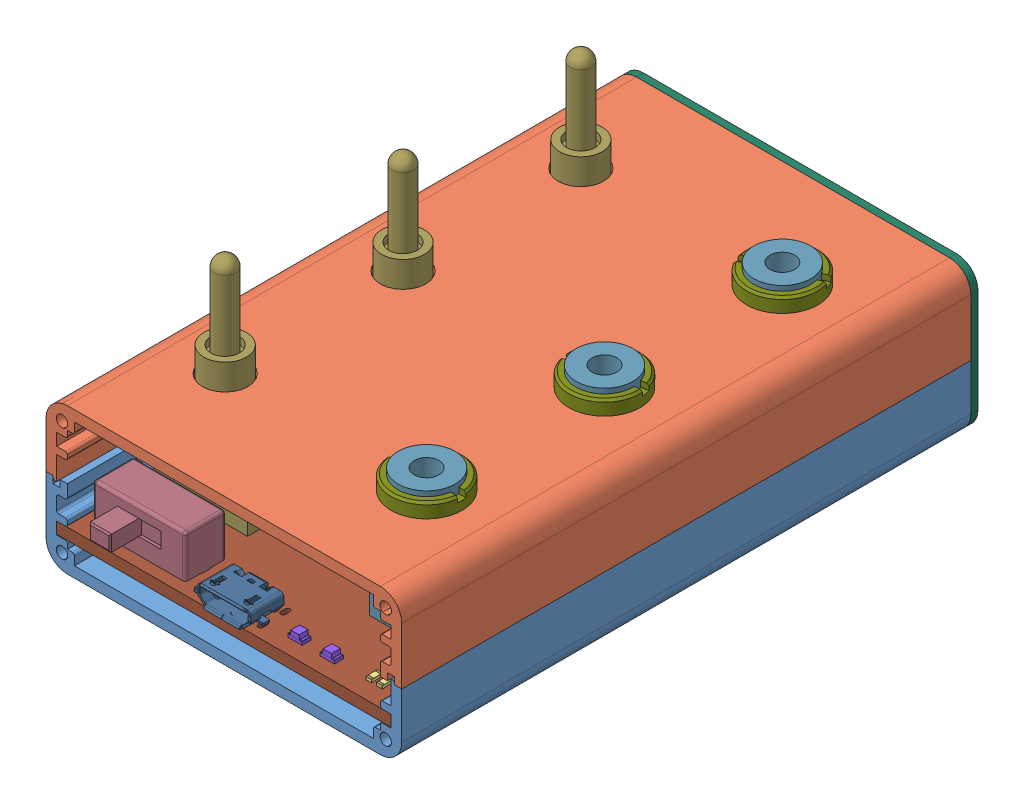
SolidWorks assembly case-full, configuration Default. Lengths in mm.
Overall size (50 35 83.41).
115 component instances, 27 part files, 20 mates.
Components (placement in the parent):
- case-1: case [Default] at (-9.9049 -10.2865 -40) size (50 11 80)
- top-case-2: top-case [Default] at (1.6835 8.41 -40) x (-1 0 0) z (0 0 1) size (50 11 80)
- PCB-assembly-1: PCB-assembly [Default] at (-5.9703 -42.4723 -73.1659) x (0 0 -1) z (0 1 0) size (82.41 47 33.7)
  - ledTruck_PCB.step-1: ledTruck_PCB.step [Default] at (-218.1999 94.1524 35.3841) size (80.38 47 12.68)
    - ledTruck.step-1: ledTruck.step [Default] at origin size (80.38 47 12.68)
      - R_0603_1608Metric.step-1: R_0603_1608Metric.step [Default] at (162.2298 -104.8258 1.65) size (1.6 0.8 0.45)
        - SOLID.step-1: SOLID.step [Default] at origin size (1.6 0.8 0.45)
      - SOT-23-5.step-1: SOT-23-5.step [Default] at (130.302 -76.708 1.65) x (0 -1 0) z (0 0 1) size (2.8 2.9 1.55)
        - SOLID-0.step-1: SOLID-0.step [Default] at origin size (2.8 2.9 1.55)
      - SOT-23-5.step-2: SOT-23-5.step [Default] at (137.16 -76.708 1.65) x (0 -1 0) z (0 0 1) size (2.8 2.9 1.55)
        - SOLID-0.step-1: SOLID-0.step [Default] at origin size (2.8 2.9 1.55)
      - R_0603_1608Metric.step-2: R_0603_1608Metric.step [Default] at (162.433 -79.248 1.65) size (1.6 0.8 0.45)
        - SOLID.step-1: SOLID.step [Default] at origin size (1.6 0.8 0.45)
      - R_0603_1608Metric.step-3: R_0603_1608Metric.step [Default] at (162.433 -76.835 1.65) x (-1 0 0) z (0 0 1) size (1.6 0.8 0.45)
        - SOLID.step-1: SOLID.step [Default] at origin size (1.6 0.8 0.45)
      - R_0603_1608Metric.step-4: R_0603_1608Metric.step [Default] at (108.1929 -114.012 1.65) size (1.6 0.8 0.45)
        - SOLID.step-1: SOLID.step [Default] at origin size (1.6 0.8 0.45)
      - R_0603_1608Metric.step-5: R_0603_1608Metric.step [Default] at (108.1929 -115.512 1.65) size (1.6 0.8 0.45)
        - SOLID.step-1: SOLID.step [Default] at origin size (1.6 0.8 0.45)
      - R_0603_1608Metric.step-6: R_0603_1608Metric.step [Default] at (152.146 -80.01 1.65) size (1.6 0.8 0.45)
        - SOLID.step-1: SOLID.step [Default] at origin size (1.6 0.8 0.45)
      - R_0603_1608Metric.step-7: R_0603_1608Metric.step [Default] at (165.1 -84.836 1.65) x (0 1 0) z (0 0 1) size (1.6 0.8 0.45)
        - SOLID.step-1: SOLID.step [Default] at origin size (1.6 0.8 0.45)
      - R_0603_1608Metric.step-8: R_0603_1608Metric.step [Default] at (137.16 -80.264 1.65) x (-1 0 0) z (0 0 1) size (1.6 0.8 0.45)
        - SOLID.step-1: SOLID.step [Default] at origin size (1.6 0.8 0.45)
      - R_0603_1608Metric.step-9: R_0603_1608Metric.step [Default] at (156.972 -111.506 1.65) x (-1 0 0) z (0 0 1) size (1.6 0.8 0.45)
        - SOLID.step-1: SOLID.step [Default] at origin size (1.6 0.8 0.45)
      - R_0603_1608Metric.step-10: R_0603_1608Metric.step [Default] at (156.972 -107.442 1.65) size (1.6 0.8 0.45)
        - SOLID.step-1: SOLID.step [Default] at origin size (1.6 0.8 0.45)
      - R_0603_1608Metric.step-11: R_0603_1608Metric.step [Default] at (132.842 -113.284 1.65) size (1.6 0.8 0.45)
        - SOLID.step-1: SOLID.step [Default] at origin size (1.6 0.8 0.45)
      - R_0603_1608Metric.step-12: R_0603_1608Metric.step [Default] at (156.972 -109.474 1.65) x (-1 0 0) z (0 0 1) size (1.6 0.8 0.45)
        - SOLID.step-1: SOLID.step [Default] at origin size (1.6 0.8 0.45)
      - R_0603_1608Metric.step-13: R_0603_1608Metric.step [Default] at (156.972 -105.283 1.65) x (-1 0 0) z (0 0 1) size (1.6 0.8 0.45)
        - SOLID.step-1: SOLID.step [Default] at origin size (1.6 0.8 0.45)
      - R_0603_1608Metric.step-14: R_0603_1608Metric.step [Default] at (132.828 -111.379 1.65) size (1.6 0.8 0.45)
        - SOLID.step-1: SOLID.step [Default] at origin size (1.6 0.8 0.45)
      - L_0805_2012Metric.step-1: L_0805_2012Metric.step [Default] at (130.336 -80.264 1.65) x (-1 0 0) z (0 0 1) size (2 1.25 1.25)
        - SOLID-1.step-1: SOLID-1.step [Default] at origin size (2 1.25 1.25)
      - C_0805_2012Metric.step-1: C_0805_2012Metric.step [Default] at (130.302 -87.122 1.65) size (2 1.25 1.25)
        - SOLID-2.step-1: SOLID-2.step [Default] at origin size (2 1.25 1.25)
      - C_0603_1608Metric.step-1: C_0603_1608Metric.step [Default] at (152.146 -78.486 1.65) x (-1 0 0) z (0 0 1) size (1.6 0.8 0.8)
        - SOLID-3.step-1: SOLID-3.step [Default] at origin size (1.6 0.8 0.8)
      - C_0805_2012Metric.step-2: C_0805_2012Metric.step [Default] at (137.16 -83.566 1.65) size (2 1.25 1.25)
        - SOLID-2.step-1: SOLID-2.step [Default] at origin size (2 1.25 1.25)
      - C_0603_1608Metric.step-2: C_0603_1608Metric.step [Default] at (152.146 -76.962 1.65) x (-1 0 0) z (0 0 1) size (1.6 0.8 0.8)
        - SOLID-3.step-1: SOLID-3.step [Default] at origin size (1.6 0.8 0.8)
      - C_0603_1608Metric.step-3: C_0603_1608Metric.step [Default] at (152.146 -75.464 1.65) x (-1 0 0) z (0 0 1) size (1.6 0.8 0.8)
        - SOLID-3.step-1: SOLID-3.step [Default] at origin size (1.6 0.8 0.8)
      - C_0805_2012Metric.step-3: C_0805_2012Metric.step [Default] at (130.302 -83.566 1.65) size (2 1.25 1.25)
        - SOLID-2.step-1: SOLID-2.step [Default] at origin size (2 1.25 1.25)
      - C_0603_1608Metric.step-4: C_0603_1608Metric.step [Default] at (162.56 -81.534 1.65) size (1.6 0.8 0.8)
        - SOLID-3.step-1: SOLID-3.step [Default] at origin size (1.6 0.8 0.8)
      - C_0603_1608Metric.step-5: C_0603_1608Metric.step [Default] at (162.56 -88.138 1.65) size (1.6 0.8 0.8)
        - SOLID-3.step-1: SOLID-3.step [Default] at origin size (1.6 0.8 0.8)
      - C_0805_2012Metric.step-4: C_0805_2012Metric.step [Default] at (137.16 -87.122 1.65) size (2 1.25 1.25)
        - SOLID-2.step-1: SOLID-2.step [Default] at origin size (2 1.25 1.25)
      - R_0603_1608Metric.step-15: R_0603_1608Metric.step [Default] at (125.984 -75.946 1.65) size (1.6 0.8 0.45)
        - SOLID.step-1: SOLID.step [Default] at origin size (1.6 0.8 0.45)
      - R_0603_1608Metric.step-16: R_0603_1608Metric.step [Default] at (114.046 -80.264 1.65) x (0 -1 0) z (0 0 1) size (1.6 0.8 0.45)
        - SOLID.step-1: SOLID.step [Default] at origin size (1.6 0.8 0.45)
      - LED_0805_2012Metric.step-1: LED_0805_2012Metric.step [Default] at (107.6929 -108.512 1.65) x (0 -1 0) z (0 0 1) size (2 1.25 1.1)
        - SOLID-4.step-1: SOLID-4.step [Default] at origin size (2 1.25 1.1)
      - LED_0805_2012Metric.step-2: LED_0805_2012Metric.step [Default] at (107.6929 -103.962 1.65) x (0 -1 0) z (0 0 1) size (2 1.25 1.1)
        - SOLID-4.step-1: SOLID-4.step [Default] at origin size (2 1.25 1.1)
      - C_0603_1608Metric.step-6: C_0603_1608Metric.step [Default] at (125.984 -77.978 1.65) x (-1 0 0) z (0 0 1) size (1.6 0.8 0.8)
        - SOLID-3.step-1: SOLID-3.step [Default] at origin size (1.6 0.8 0.8)
      - SW_CuK_JS202011AQN_DPDT_Angled.step-1: SW_CuK_JS202011AQN_DPDT_Angled.step [Default] at (111.474 -79.012 1.65) x (0 -1 0) z (0 0 1) size (9 5.6 6.5) (hidden)
        - SOLID-5.step-1: SOLID-5.step [Default] at origin size (9 5.6 6.5)
      - JST_XH_S2B-XH-A_1x02_P2.50mm_Horizontal.step-1: JST_XH_S2B-XH-A_1x02_P2.50mm_Horizontal.step [Default] at (179.578 -78.012 1.65) size (7.4 11.5 9.5)
        - SOLID-6.step-1: SOLID-6.step [Default] at origin size (7.4 11.5 9.5)
      - USB_Micro-B_Molex_47346-0001.step-1: USB_Micro-B_Molex_47346-0001.step [Default] at (108.4213 -96.0044 1.65) x (0 -1 0) z (0 0 1) size (7.98 5.42 2.94)
        - SOLID-7.step-1: SOLID-7.step [Default] at origin size (7.98 5.42 2.94)
      - Crystal_SMD_0603-4Pin_6.0x3.5mm.step-1: Crystal_SMD_0603-4Pin_6.0x3.5mm.step [Default] at (162.56 -84.856 1.65) x (0 1 0) z (0 0 1) size (6 3.5 1.03)
        - SOLID-8.step-1: SOLID-8.step [Default] at origin size (6 3.5 1.03) (hidden)
      - 7101 ToggleSwitch.step-1: 7101 ToggleSwitch.step [Default] at (121.534 -82.012 10.15) size (0.36 0.5 1.28) (hidden)
        - SOLID-9.step-1: SOLID-9.step [Default] at origin size (0.28 0.5 0.35) (hidden)
        - SOLID-10.step-1: SOLID-10.step [Default] at origin size (0.24 0.24 0.35)
        - SOLID-11.step-1: SOLID-11.step [Default] at origin size (0.12 0.21 0.43)
        - SOLID-12.step-1: SOLID-12.step [Default] at origin size (0.36 0.31 0.06)
        - SOLID-13.step-1: SOLID-13.step [Default] at origin size (0.36 0.31 0.06)
        - SOLID-14.step-1: SOLID-14.step [Default] at origin size (0.08 0.03 0.16)
        - SOLID-15.step-1: SOLID-15.step [Default] at origin size (0.08 0.03 0.16)
        - SOLID-16.step-1: SOLID-16.step [Default] at origin size (0.08 0.03 0.16)
      - 7101 ToggleSwitch.step-2: 7101 ToggleSwitch.step [Default] at (146.534 -82.012 10.15) size (0.36 0.5 1.28) (hidden)
        - SOLID-9.step-1: SOLID-9.step [Default] at origin size (0.28 0.5 0.35) (hidden)
        - SOLID-10.step-1: SOLID-10.step [Default] at origin size (0.24 0.24 0.35)
        - SOLID-11.step-1: SOLID-11.step [Default] at origin size (0.12 0.21 0.43)
        - SOLID-12.step-1: SOLID-12.step [Default] at origin size (0.36 0.31 0.06)
        - SOLID-13.step-1: SOLID-13.step [Default] at origin size (0.36 0.31 0.06)
        - SOLID-14.step-1: SOLID-14.step [Default] at origin size (0.08 0.03 0.16)
        - SOLID-15.step-1: SOLID-15.step [Default] at origin size (0.08 0.03 0.16)
        - SOLID-16.step-1: SOLID-16.step [Default] at origin size (0.08 0.03 0.16)
      - 7101 ToggleSwitch.step-3: 7101 ToggleSwitch.step [Default] at (171.534 -82.012 10.15) size (0.36 0.5 1.28) (hidden)
        - SOLID-9.step-1: SOLID-9.step [Default] at origin size (0.28 0.5 0.35) (hidden)
        - SOLID-10.step-1: SOLID-10.step [Default] at origin size (0.24 0.24 0.35)
        - SOLID-11.step-1: SOLID-11.step [Default] at origin size (0.12 0.21 0.43)
        - SOLID-12.step-1: SOLID-12.step [Default] at origin size (0.36 0.31 0.06)
        - SOLID-13.step-1: SOLID-13.step [Default] at origin size (0.36 0.31 0.06)
        - SOLID-14.step-1: SOLID-14.step [Default] at origin size (0.08 0.03 0.16)
        - SOLID-15.step-1: SOLID-15.step [Default] at origin size (0.08 0.03 0.16)
        - SOLID-16.step-1: SOLID-16.step [Default] at origin size (0.08 0.03 0.16)
      - COMPOUND.step-1: COMPOUND.step [Default] at origin size (80 47 1.6)
  - toggle-switch-2: toggle-switch [Default] at (-47.8013 13.9041 36.9841) x (1 0 0) z (0 -1 0) size (6.9 31.5 13.2)
  - toggle-switch-3: toggle-switch [Default] at (-72.8013 13.9041 36.9841) x (1 0 0) z (0 -1 0) size (6.9 31.5 13.2)
  - toggle-switch-4: toggle-switch [Default] at (-97.8013 13.9041 36.9841) x (1 0 0) z (0 -1 0) size (6.9 31.5 13.2)
  - slideswitch-1: slideswitch [Default] at (-109.6165 12.0841 36.9841) x (0 -1 0) z (-1 0 0) size (13 8.2 9.7)
  - 3,5mmjack_MultiComp-1: 3,5mmjack_MultiComp [Default] at (-97.9637 -15.2725 36.9841) size (9 10.5 21.9)
  - 3,5mmjack_MultiComp-4: 3,5mmjack_MultiComp [Default] at (-72.9637 -15.2725 36.9841) size (9 10.5 21.9)
  - 3,5mmjack_MultiComp-5: 3,5mmjack_MultiComp [Default] at (-47.9637 -15.2725 36.9841) size (9 10.5 21.9)
- case-lid-1: case-lid [Default] at (-11.7051 -0.4225 -41) size (50 20.5 1)
- case-lid-usb-1: case-lid-usb [Default] at (-11.7051 -0.4225 40) size (50 20.5 1) (hidden)
- ringM8-1: ringM8 [Default] at (9.3893 9.3118 25) x (1 0 0) z (0 1 0) size (10 10 2)
- ringM8-2: ringM8 [Default] at (9.3893 9.3118 0) x (0.982082 0 -0.188455) z (0 1 0) size (10 10 2)
- ringM8-3: ringM8 [Default] at (9.3893 9.3118 -25) x (0.918365 0 -0.395734) z (0 1 0) size (10 10 2)
Mates (geometry in assembly coordinates):
- Coincident1: coincident aligned: plane of case-1 through (-27.6107 -2.4882 40) normal (1 0 0); plane of case-2 through (-27.6107 2.6118 40) normal (1 0 0)
- Coincident3: coincident aligned: plane of case-1 through (-27.6107 -2.4882 40) normal (1 0 0); plane of case-2 through (-27.6107 2.6118 40) normal (1 0 0)
- Parallel2: parallel aligned: plane of case-1 through (19.3893 -4.4882 40) normal (-1 0 0); plane of case-2 through (19.3893 0.6118 40) normal (-1 0 0)
- Coincident6: coincident anti-aligned: plane of case-1 through (19.8933 -1.6882 40) normal (0 1 0); plane of case-2 through (20.8893 -1.6882 40) normal (0 -1 0)
- Coincident7: coincident aligned: plane of case-1 through (-26.1107 -8.1882 40) normal (0 0 1); plane of case-2 through (17.8893 6.3118 40) normal (0 0 1)
- Coincident9: coincident anti-aligned: plane of case-1 through (-27.6107 -5.4882 40) normal (1 0 0); plane of PCB-assembly-1/ledTruck_PCB.step-1/ledTruck.step-1/COMPOUND.step-1 through (-27.6107 -7.0882 40) normal (-1 0 0)
- Coincident10: coincident anti-aligned: plane of case-1 through (19.3893 -5.4882 40) normal (0 -1 0); plane of PCB-assembly-1/ledTruck_PCB.step-1/ledTruck.step-1/COMPOUND.step-1 through (-4.1107 -5.4882 0) normal (0 1 0)
- Coincident11: coincident aligned: plane of case-1 through (-26.1107 -8.1882 40) normal (0 0 1); plane of PCB-assembly-1/ledTruck_PCB.step-1/ledTruck.step-1/COMPOUND.step-1 through (19.3893 -7.0882 40) normal (0 0 1)
- Coincident12: coincident anti-aligned: plane of case-2 through (17.8893 6.3118 -40) normal (0 0 -1); plane of case-lid-1 through (17.8893 6.3118 -40) normal (0 0 1)
- Coincident13: coincident aligned: plane of case-2 through (17.8893 9.3118 40) normal (0 1 0); plane of case-lid-1 through (-26.1107 9.3118 -40) normal (0 1 0)
- Coincident14: coincident aligned: plane of case-1 through (-29.1107 -0.1882 40) normal (-1 0 0); plane of case-lid-1 through (-29.1107 6.3118 -40) normal (-1 0 0)
- Coincident15: coincident anti-aligned: plane of case-2 through (17.8893 6.3118 40) normal (0 0 1); plane of case-lid-usb-1 through (17.8893 6.3118 40) normal (0 0 -1)
- Coincident16: coincident aligned: plane of case-2 through (17.8893 9.3118 40) normal (0 1 0); plane of case-lid-usb-1 through (-26.1107 9.3118 41) normal (0 1 0)
- Coincident18: coincident aligned: plane of case-2 through (-29.1107 6.3118 40) normal (-1 0 0); plane of case-lid-usb-1 through (-29.1107 6.3118 41) normal (-1 0 0)
- Coincident19: coincident anti-aligned: plane of top-case-2 through (17.8893 9.3118 40) normal (0 1 0); plane of ringM8-1 through (9.3893 9.3118 25) normal (0 -1 0)
- Concentric1: concentric anti-aligned: cylinder of PCB-assembly-1/3,5mmjack_MultiComp-1 through (9.3893 12.0118 25) axis (0 -1 0) radius 4; circle of ringM8-1
- Coincident20: coincident anti-aligned: plane of top-case-2 through (17.8893 9.3118 40) normal (0 1 0); plane of ringM8-2 through (9.3893 9.3118 0) normal (0 -1 0)
- Concentric2: concentric anti-aligned: cylinder of PCB-assembly-1/3,5mmjack_MultiComp-4 through (9.3893 12.0118 0) axis (0 -1 0) radius 4; circle of ringM8-2
- Coincident21: coincident anti-aligned: plane of top-case-2 through (17.8893 9.3118 40) normal (0 1 0); plane of ringM8-3 through (9.3893 9.3118 -25) normal (0 -1 0)
- Concentric3: concentric anti-aligned: cylinder of PCB-assembly-1/3,5mmjack_MultiComp-5 through (9.3893 12.0118 -25) axis (0 -1 0) radius 4; circle of ringM8-3
